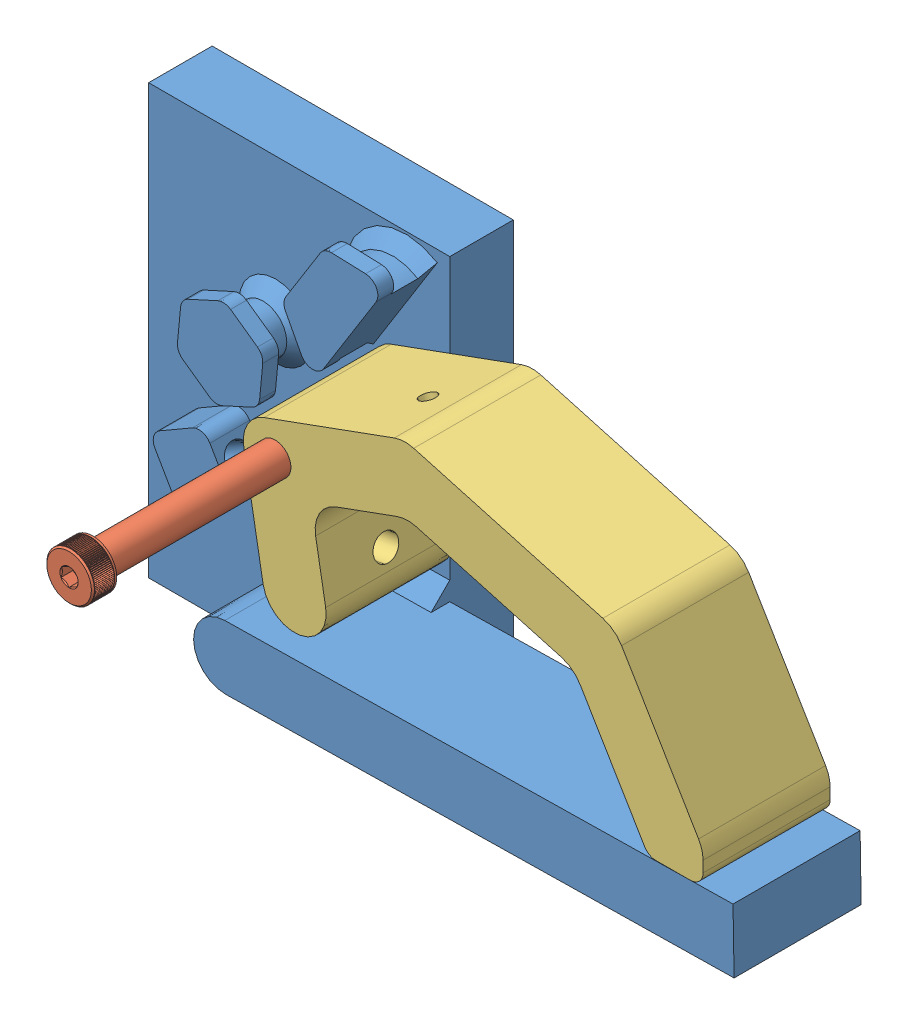
SolidWorks assembly Gripper Assembly Half Size, configuration Default. Lengths in mm.
Overall size (142.43 85.72 79.45).
3 component instances, 3 part files, 8 mates.
Components (placement in the parent):
- BackPanelwithRestClaw^Gripper Assembly Half Size-1: BackPanelwithRestClaw^Gripper Assembly Half Size [Default] at origin size (142.43 85.72 38.1) (virtual)
- 91273A353_18-8 STAINLESS STEEL SHOULDER SCREW-1: 91273A353_18-8 STAINLESS STEEL SHOULDER SCREW [91273A353] at (-13.7361 77.6056 224.3113) x (0.999041 -0.043795 0) z (0 0 1) size (9.53 9.53 53.09)
- Moving Claw Half Size-1: Moving Claw Half Size [Default] at (-13.7361 77.6056 157.7425) x (0 0 1) z (0.075564 0.997141 0) size (25.4 93.86 45.65)
Mates (geometry in assembly coordinates):
- Coincident34: coincident anti-aligned: plane of BackPanel-1 through (-64.4091 18.8681 170.4425) normal (0 0 1); plane of MovingClaw-1 through (-5.8703 33.8571 170.4425) normal (0 0 -1)
- Concentric1: concentric aligned: circle of MovingClaw-1; circle of BackPanelwithRestClaw^Gripper-1
- Coincident37: coincident: plane of BackPanel-1 through (-64.4091 18.8681 170.4425) normal (0 0 1); plane of RestClaw-1 through (-36.3733 37.952 157.7425) normal (0 0 -1)
- Concentric5: concentric aligned: cylinder of MovingClaw-1 through (-13.7361 77.6056 221.2425) axis (0 0 -1) radius 3.175; cylinder of 91273A353_18-8 STAINLESS STEEL SHOULDER SCREW-1 through (-13.7361 77.6056 173.6175) axis (0 0 -1) radius 3.175
- Coincident41: coincident anti-aligned: circle of MovingClaw-1; plane of 91273A353_18-8 STAINLESS STEEL SHOULDER SCREW-1 through (-13.9447 72.8477 221.2425) normal (0 0 -1)
- Concentric6: concentric anti-aligned: cylinder of BackPanelwithRestClaw^Gripper Assembly Half Size-1 through (-13.7361 77.6056 145.0425) axis (0 0 1) radius 3.175; cylinder of Moving Claw Half Size-1 through (-13.2565 99.3916 196.5743) axis (0 0 -1) radius 3.175
- Coincident42: coincident aligned: circle of BackPanelwithRestClaw^Gripper Assembly Half Size-1; circle of Moving Claw Half Size-1
- Concentric7: concentric aligned: cylinder of 91273A353_18-8 STAINLESS STEEL SHOULDER SCREW-1 through (-13.7361 77.6056 171.9238) axis (0 0 -1) radius 3.175; cylinder of Moving Claw Half Size-1 through (-13.7361 77.6056 183.1425) axis (0 0 -1) radius 3.175
